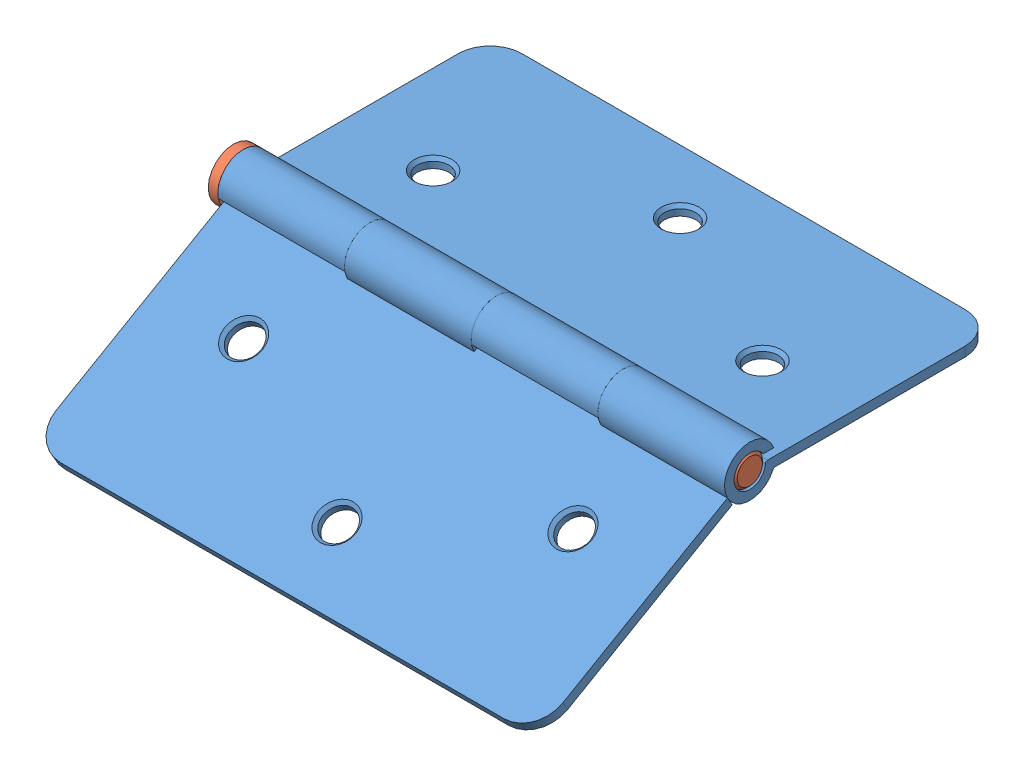
SolidWorks assembly Assem1, configuration Default. Lengths in mm.
Overall size (81.5 28.43 74.77).
3 component instances, 2 part files, 4 mates.
Components (placement in the parent):
- Part1-1: Part1 [Default] at (37.8612 47.6449 53.1797) size (80 8 43)
- Part2-1: Part2 [Default] at (-3.6388 49.0201 74.6778) x (0 0.999715 -0.023858) z (1 0 0) size (8 8 81.5)
- Part1-2: Part1 [Default] at (37.8612 37.0801 92.608) x (-1 0 0) z (0 0.5 -0.866025) size (80 8 43)
Mates (geometry in assembly coordinates):
- Hinge1: hinge anti-aligned: cylinder of Part1-2 through (17.8612 49.0201 74.6778) axis (-1 0 0) radius 2.5; cylinder of Part1-1 through (17.8612 49.0201 74.6778) axis (1 0 0) radius 2.5; plane of Part1-2 through (17.8612 47.4711 77.0103) normal (1 0 0); plane of Part1-1 through (17.8612 48.8449 71.8832) normal (-1 0 0)
- Concentric1: concentric aligned: cylinder of Part2-1 through (77.8612 49.0201 74.6778) axis (-1 0 0) radius 2.5; cylinder of Part1-2 through (17.8612 49.0201 74.6778) axis (-1 0 0) radius 2.5
- Coincident1: coincident anti-aligned: plane of Part2-1 through (-2.1388 49.0201 74.6778) normal (1 0 0); plane of Part1-2 through (-2.1388 47.1292 78.2026) normal (-1 0 0)
- LimitAngle2: limit planar angle = 0.523599 rad aligned: plane of Part1-1 through (72.8612 49.1449 40.6797) normal (0 1 0); plane of Part1-2 through (2.8612 32.1292 104.1833) normal (0 0.866025 0.5)
